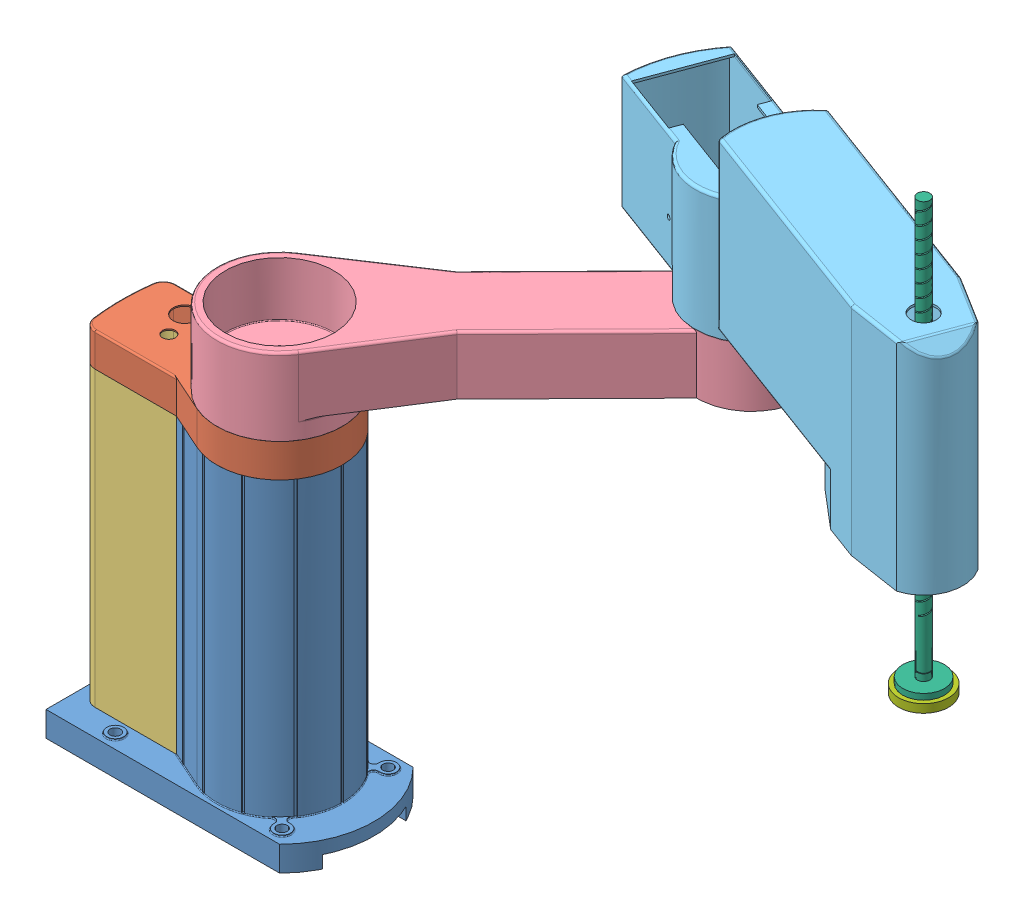
SolidWorks assembly new_complete_assembly_2023, configuration Default. Lengths in mm.
Overall size (876.38 845.02 510.17).
8 component instances, 7 part files, 7 mates.
Components (placement in the parent):
- new_DE_2023-1: new_DE_2023 [Default] at origin size (313.14 421.07 160)
  - khau0_base-1: khau0_base [Default] at origin size (313.14 381.07 160)
  - khau0_base_connector-1: khau0_base_connector [Default] at (145 381.07 0) size (265 44.5 150)
  - khau0_base_support-1: khau0_base_support [Default] at (145 30 0) size (115 351.07 97)
- khau1_arm-1: khau1_arm [Default] at (60 443.07 0) x (0.701786 0 -0.712388) z (0.712388 0 0.701786) size (541 95 150)
- khau2_cover-1: khau2_cover [Default] at (340.7144 524.57 -284.9552) x (0.937437 0 0.348155) z (-0.348155 0 0.937437) size (557.5 270.16 135)
- lead_screw-2: lead_screw [Default] at (668.8174 340.0206 -163.1011) x (0.706187 0 0.708025) z (-0.708025 0 0.706187) size (50 505 50)
- new_end_effector-1: new_end_effector [Default] at (668.8174 330.0206 -163.1011) x (0.984524 0 -0.175249) z (0.175249 0 0.984524) size (60 10 60)
Mates (geometry in assembly coordinates):
- Concentric18: concentric aligned: cylinder of new_DE_2023-1/khau0_base_connector-1 through (60 406.07 0) axis (0 1 0) radius 70; cylinder of khau1_arm-1 through (60 421.07 0) axis (0 1 0) radius 65
- Coincident18: coincident anti-aligned: plane of new_DE_2023-1/khau0_base_connector-1 through (-112.8328 421.07 -33.5) normal (0 1 0); plane of khau1_arm-1 through (60 421.07 0) normal (0 -1 0)
- Concentric19: concentric aligned: cylinder of khau1_arm-1 through (340.7144 317.0954 -284.9552) axis (0 1 0) radius 57.5; cylinder of khau2_cover-1 through (340.7144 784.4857 -284.9552) axis (0 1 0) radius 66
- Coincident19: coincident anti-aligned: plane of khau1_arm-1 through (387.0322 516.07 -331.9728) normal (0 1 0); plane of khau2_cover-1 through (403.9914 516.07 -261.4547) normal (0 -1 0)
- Concentric20: concentric anti-aligned: cylinder of khau2_cover-1 through (668.8174 420.8697 -163.1011) axis (0 -1 0) radius 11.5; cylinder of lead_screw-2 through (668.8174 845.0206 -163.1011) axis (0 1 0) radius 25
- Concentric21: concentric anti-aligned: cylinder of lead_screw-2 through (668.8174 845.0206 -163.1011) axis (0 1 0) radius 25; cylinder of new_end_effector-1 through (668.8174 340.0206 -163.1011) axis (0 -1 0) radius 30
- Coincident22: coincident anti-aligned: plane of lead_screw-2 through (668.8174 340.0206 -163.1011) normal (0 -1 0); plane of new_end_effector-1 through (668.8174 340.0206 -163.1011) normal (0 1 0)
